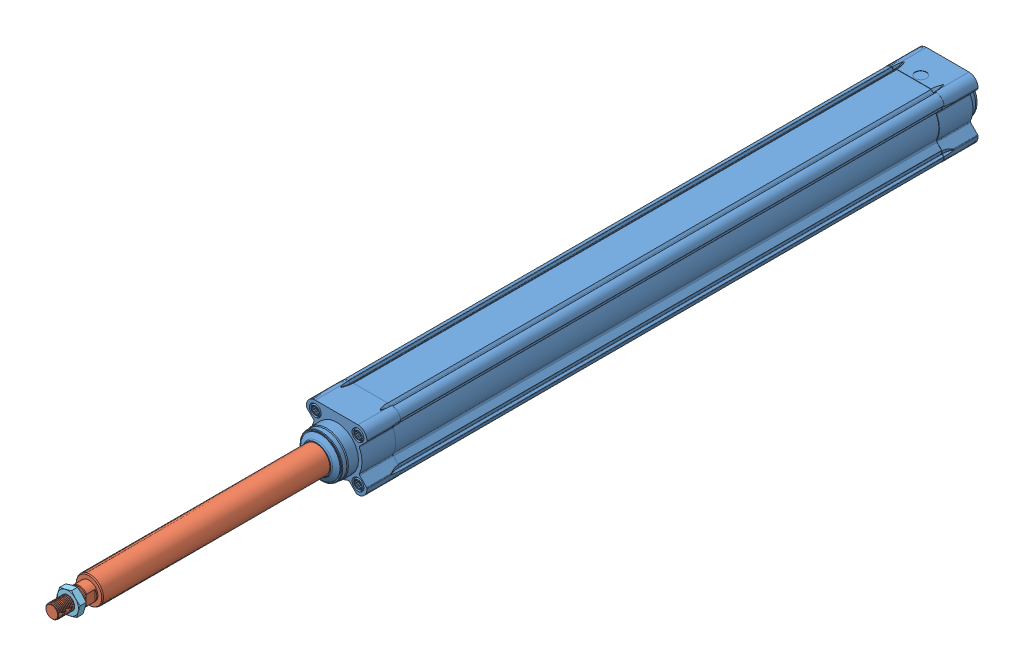
SolidWorks assembly Actuator, configuration Default. Lengths in mm.
Overall size (54 54 816.32).
5 component instances, 5 part files, 12 mates.
Components (placement in the parent):
- ESBF-BS-40-400---(ZR_-_-)-1: ESBF-BS-40-400---(ZR_-_-) [Default] at origin size (54 54 569)
- ESBF-BS-40-400-5P---(KS_0)-1: ESBF-BS-40-400-5P---(KS_0) [Default] at (0 0 200) size (40 40 567.92)
- 717739 GUK M10x0_75-1: 717739 GUK M10x0_75 [Default] at (0 0 -540.8) x (0 1 0) z (0 0 -1) size (17.75 17.75 7.6)
- ESBF-BS-40-ESBF-BS-40---(KSA)-1: ESBF-BS-40-ESBF-BS-40---(KSA) [Default] at (0 0 -514) size (10 10 48.4)
- DIN-439-B - M12x1_25(F)-1: DIN-439-B - M12x1_25(F) [Default] at (0 0 233.267) x (0.962014 -0.272999 0) z (0.272999 0.962014 0) size (19 6.85 21.94)
Mates (geometry in assembly coordinates):
- LimitDistance1: limit distance = 200 mm anti-aligned: plane of ESBF-BS-40-400---(ZR_-_-)-1 through (0 0 -514) normal (0 0 1); plane of ESBF-BS-40-400-5P---(KS_0)-1 through (0 0 -314) normal (0 0 -1)
- Coincident1: coincident anti-aligned: line of ESBF-BS-40-400---(ZR_-_-)-1 through (0 0 80.9) axis (0 0 -1); line of ESBF-BS-40-400-5P---(KS_0)-1 through (0 0 119.1) axis (0 0 1)
- Angle3: planar angle = 0 rad aligned: plane of ESBF-BS-40-400-5P---(KS_0)-1 through (0 0 200) normal (1 0 0); plane of ESBF-BS-40-400---(ZR_-_-)-1 through (0 0 0) normal (1 0 0)
- Distance2: distance = 0 mm anti-aligned: plane of ESBF-BS-40-400---(ZR_-_-)-1 through (0 0 -540.8) normal (0 0 1); plane of 717739 GUK M10x0_75-1 through (0 0 -540.8) normal (0 0 -1)
- Coincident3: coincident anti-aligned: line of ESBF-BS-40-400---(ZR_-_-)-1 through (0 0 50) axis (0 0 -1); line of 717739 GUK M10x0_75-1 through (0 0 -621.7) axis (0 0 1)
- Angle9: planar angle = 0 rad aligned: plane of 717739 GUK M10x0_75-1 through (0 0 -540.8) normal (0 1 0); plane of ESBF-BS-40-400---(ZR_-_-)-1 through (0 0 0) normal (0 1 0)
- Distance3: distance = 0 mm anti-aligned: plane of ESBF-BS-40-400---(ZR_-_-)-1 through (0 0 -514) normal (0 0 -1); plane of ESBF-BS-40-ESBF-BS-40---(KSA)-1 through (0 0 -514) normal (0 0 1)
- Coincident4: coincident anti-aligned: line of ESBF-BS-40-400---(ZR_-_-)-1 through (0 0 -80.9) axis (0 0 1); line of ESBF-BS-40-ESBF-BS-40---(KSA)-1 through (0 0 -433.1) axis (0 0 -1)
- Angle12: planar angle = 0 rad aligned: plane of ESBF-BS-40-ESBF-BS-40---(KSA)-1 through (0 0 -514) normal (1 0 0); plane of ESBF-BS-40-400---(ZR_-_-)-1 through (0 0 0) normal (1 0 0)
- Distance4: distance = 253.5 mm aligned: plane of ESBF-BS-40-400---(ZR_-_-)-1 through (-26 18.2218 0) normal (0 0 1); plane of ESBF-BS-40-400-5P---(KS_0)-1 through (0 0 253.5) normal (0 0 1)
- Concentric1: concentric anti-aligned: cylinder of ESBF-BS-40-400-5P---(KS_0)-1 through (0 0 229.5) axis (0 0 1) radius 6; cylinder of DIN-439-B - M12x1_25(F)-1 through (0 0 239.267) axis (0 0 -1) radius 5.3235
- Coincident5: coincident anti-aligned: circle of ESBF-BS-40-400-5P---(KS_0)-1; plane of DIN-439-B - M12x1_25(F)-1 through (0 0 233.267) normal (0 0 -1)
